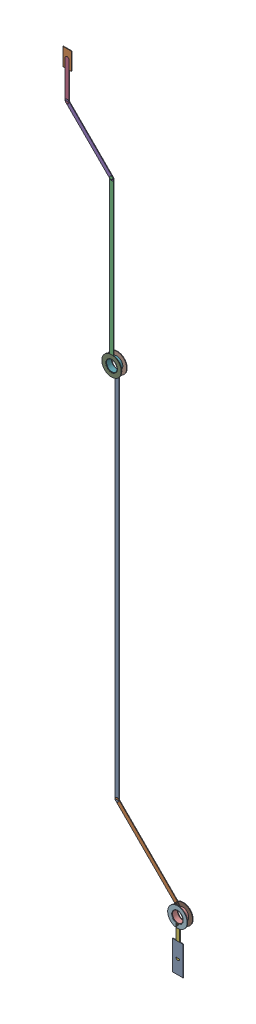
SolidWorks assembly INT1, configuration Predeterminado. Lengths in mm.
Overall size (8.11 48.74 0.39).
38 component instances, 10 part files, 0 mates.
Components (placement in the parent):
- Track (21.9mm,15.3mm)(21.9mm,40mm) on Bottom Layer-1: Track (21.9mm,15.3mm)(21.9mm,40mm) on Bottom Layer [Predeterminado] at origin size (0.25 24.49 0.04)
  - Track (21.9mm,15.3mm)(21.9mm,40mm) on Bottom Layer-1-1: Track (21.9mm,15.3mm)(21.9mm,40mm) on Bottom Layer-1 [Predeterminado] at (-68.317 -44.187 -0.4013) size (0.25 24.49 0.04)
    - Track (21.9mm,15.3mm)(21.9mm,40mm) on Bottom Layer-Part-1-1: Track (21.9mm,15.3mm)(21.9mm,40mm) on Bottom Layer-Part-1 [Predeterminado] at origin size (0.25 24.49 0.04)
- Track (21.9mm,15.3mm)(26.2mm,11mm) on Bottom Layer-1: Track (21.9mm,15.3mm)(26.2mm,11mm) on Bottom Layer [Predeterminado] at origin size (4.28 4.28 0.04)
  - Track (21.9mm,15.3mm)(26.2mm,11mm) on Bottom Layer-1-1: Track (21.9mm,15.3mm)(26.2mm,11mm) on Bottom Layer-1 [Predeterminado] at (-68.317 -44.187 -0.4013) size (4.28 4.28 0.04)
    - Track (21.9mm,15.3mm)(26.2mm,11mm) on Bottom Layer-Part-1-1: Track (21.9mm,15.3mm)(26.2mm,11mm) on Bottom Layer-Part-1 [Predeterminado] at origin size (4.28 4.28 0.04)
- Track (21.9mm,40mm)(21.9mm,50.6mm) on Top Layer-1: Track (21.9mm,40mm)(21.9mm,50.6mm) on Top Layer [Predeterminado] at origin size (0.25 10.39 0.04)
  - Track (21.9mm,40mm)(21.9mm,50.6mm) on Top Layer-1-1: Track (21.9mm,40mm)(21.9mm,50.6mm) on Top Layer-1 [Predeterminado] at (-68.317 -44.187 -0.0457) size (0.25 10.39 0.04)
    - Track (21.9mm,40mm)(21.9mm,50.6mm) on Top Layer-Part-1-1: Track (21.9mm,40mm)(21.9mm,50.6mm) on Top Layer-Part-1 [Predeterminado] at origin size (0.25 10.39 0.04)
- Track (19mm,53.5mm)(19mm,55.903mm) on Top Layer-1: Track (19mm,53.5mm)(19mm,55.903mm) on Top Layer [Predeterminado] at origin size (0.25 2.66 0.04)
  - Track (19mm,53.5mm)(19mm,55.903mm) on Top Layer-1-1: Track (19mm,53.5mm)(19mm,55.903mm) on Top Layer-1 [Predeterminado] at (-68.317 -44.187 -0.0457) size (0.25 2.66 0.04)
    - Track (19mm,53.5mm)(19mm,55.903mm) on Top Layer-Part-1-1: Track (19mm,53.5mm)(19mm,55.903mm) on Top Layer-Part-1 [Predeterminado] at origin size (0.25 2.66 0.04)
- Track (19mm,53.5mm)(21.9mm,50.6mm) on Top Layer-1: Track (19mm,53.5mm)(21.9mm,50.6mm) on Top Layer [Predeterminado] at origin size (3.15 3.15 0.04)
  - Track (19mm,53.5mm)(21.9mm,50.6mm) on Top Layer-1-1: Track (19mm,53.5mm)(21.9mm,50.6mm) on Top Layer-1 [Predeterminado] at (-68.317 -44.187 -0.0457) size (3.15 3.15 0.04)
    - Track (19mm,53.5mm)(21.9mm,50.6mm) on Top Layer-Part-1-1: Track (19mm,53.5mm)(21.9mm,50.6mm) on Top Layer-Part-1 [Predeterminado] at origin size (3.15 3.15 0.04)
- Track (26.225mm,8.691mm)(26.225mm,10.975mm) on Top Layer-1: Track (26.225mm,8.691mm)(26.225mm,10.975mm) on Top Layer [Predeterminado] at origin size (0.25 2.11 0.04)
  - Track (26.225mm,8.691mm)(26.225mm,10.975mm) on Top Layer-1-1: Track (26.225mm,8.691mm)(26.225mm,10.975mm) on Top Layer-1 [Predeterminado] at (-68.317 -44.187 -0.0457) size (0.25 2.11 0.04)
    - Track (26.225mm,8.691mm)(26.225mm,10.975mm) on Top Layer-Part-1-1: Track (26.225mm,8.691mm)(26.225mm,10.975mm) on Top Layer-Part-1 [Predeterminado] at origin size (0.25 2.11 0.04)
- Via (21.9mm,40mm) from Top Layer to Bottom Layer-1: Via (21.9mm,40mm) from Top Layer to Bottom Layer [Predeterminado] at origin size (1.27 1.27 0.39)
  - Via Hole-1: Via Hole [Predeterminado] at (21.9 40 -0.4013) size (0.76 0.76 0.39)
    - Via Hole-Part-1-1: Via Hole-Part-1 [Predeterminado] at origin size (0.76 0.76 0.39)
  - Via Top Layer-1: Via Top Layer [Predeterminado] at (21.9 40 -0.4013) size (1.27 1.27 0.04)
    - Via Top Layer-Part-1-1: Via Top Layer-Part-1 [Predeterminado] at origin size (1.27 1.27 0.04)
  - Via Top Layer-2: Via Top Layer [Predeterminado] at (21.9 40 -0.0457) size (1.27 1.27 0.04)
    - Via Top Layer-Part-1-1: Via Top Layer-Part-1 [Predeterminado] at origin size (1.27 1.27 0.04)
- Via (26.2mm,11mm) from Top Layer to Bottom Layer-1: Via (26.2mm,11mm) from Top Layer to Bottom Layer [Predeterminado] at origin size (1.27 1.27 0.39)
  - Via Hole-1: Via Hole [Predeterminado] at (26.2 11 -0.4013) size (0.76 0.76 0.39)
    - Via Hole-Part-1-1: Via Hole-Part-1 [Predeterminado] at origin size (0.76 0.76 0.39)
  - Via Top Layer-1: Via Top Layer [Predeterminado] at (26.2 11 -0.4013) size (1.27 1.27 0.04)
    - Via Top Layer-Part-1-1: Via Top Layer-Part-1 [Predeterminado] at origin size (1.27 1.27 0.04)
  - Via Top Layer-2: Via Top Layer [Predeterminado] at (26.2 11 -0.0457) size (1.27 1.27 0.04)
    - Via Top Layer-Part-1-1: Via Top Layer-Part-1 [Predeterminado] at origin size (1.27 1.27 0.04)
- Pad RAK4600-21(26.225mm,8.691mm) on Top Layer-1: Pad RAK4600-21(26.225mm,8.691mm) on Top Layer [Predeterminado] at origin size (0.7 1.9 0.04)
  - Pad RAK4600-21(26.225mm,8.691mm) on Top Layer-1-1: Pad RAK4600-21(26.225mm,8.691mm) on Top Layer-1 [Predeterminado] at (-68.317 -44.187 -0.0457) size (0.7 1.9 0.04)
    - Pad RAK4600-21(26.225mm,8.691mm) on Top Layer-Part-1-1: Pad RAK4600-21(26.225mm,8.691mm) on Top Layer-Part-1 [Predeterminado] at origin size (0.7 1.9 0.04)
- Pad ADXL345-8(19mm,55.903mm) on Top Layer-1: Pad ADXL345-8(19mm,55.903mm) on Top Layer [Predeterminado] at origin size (0.55 1.15 0.04)
  - Pad ADXL345-8(19mm,55.903mm) on Top Layer-1-1: Pad ADXL345-8(19mm,55.903mm) on Top Layer-1 [Predeterminado] at (-68.317 -44.187 -0.0457) size (0.55 1.15 0.04)
    - Pad ADXL345-8(19mm,55.903mm) on Top Layer-Part-1-1: Pad ADXL345-8(19mm,55.903mm) on Top Layer-Part-1 [Predeterminado] at origin size (0.55 1.15 0.04)
